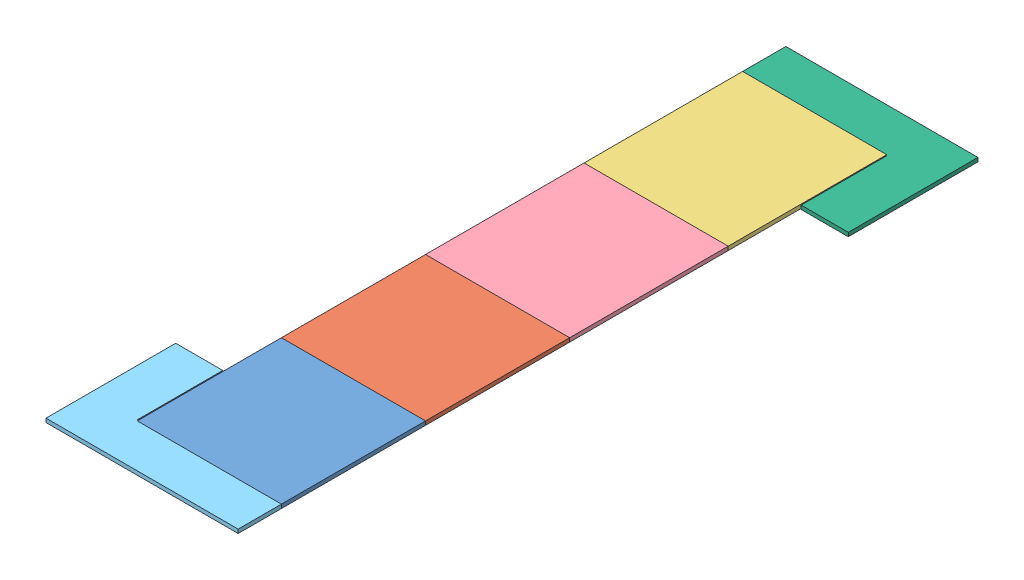
SolidWorks assembly flat, configuration Default. Lengths in mm.
Overall size (250 4 720).
6 component instances, 6 part files, 16 mates.
Components (placement in the parent):
- A-1: A [Default] at (-59.848 -4 229.8629) size (150 4 150)
- B-1: B [Default] at (-59.848 -4 229.8629) size (150 4 150)
- C-1: C [Default] at (-59.848 -4 229.8629) size (150 4 165)
- D-1: D [Default] at (-59.848 -4 229.8629) size (150 4 165)
- EA-1: EA [Default] at (-59.848 -4 229.8629) size (200 4 135)
- EC-1: EC [Default] at (-59.848 -4 229.8629) size (200 4 135)
Mates (geometry in assembly coordinates):
- Coincident3: coincident aligned: line of C-1 through (140.152 0 -280.1371) axis (-1 0 0); line of D-1 through (140.152 0 -280.1371) axis (-1 0 0)
- Coincident4: coincident aligned: line of C-1 through (-9.848 4 -445.1371) axis (1 0 0); line of EC-1 through (-9.848 4 -445.1371) axis (1 0 0)
- Coincident5: coincident aligned: plane of C-1 through (-9.848 0 229.8629) normal (-1 0 0); plane of EC-1 through (-9.848 0 229.8629) normal (-1 0 0)
- Coincident6: coincident aligned: plane of D-1 through (-9.848 0 229.8629) normal (-1 0 0); plane of EC-1 through (-9.848 0 229.8629) normal (-1 0 0)
- Coincident7: coincident aligned: line of A-1 through (140.152 4 184.8629) axis (-1 0 0); line of EA-1 through (140.152 4 184.8629) axis (-1 0 0)
- Coincident9: coincident aligned: plane of A-1 through (140.152 0 229.8629) normal (1 0 0); plane of EA-1 through (140.152 0 229.8629) normal (1 0 0)
- Coincident10: coincident aligned: plane of B-1 through (140.152 0 229.8629) normal (1 0 0); plane of EA-1 through (140.152 0 229.8629) normal (1 0 0)
- Coincident12: coincident aligned: line of A-1 through (140.152 4 34.8629) axis (-1 0 0); line of B-1 through (140.152 4 34.8629) axis (-1 0 0)
- Coincident13: coincident aligned: line of B-1 through (140.152 0 -115.1371) axis (-1 0 0); line of D-1 through (140.152 0 -115.1371) axis (-1 0 0)
- Coincident14: coincident aligned: plane of B-1 through (-9.848 0 229.8629) normal (-1 0 0); plane of D-1 through (-9.848 0 229.8629) normal (-1 0 0)
- Coincident18: coincident aligned: plane of EC-1 through (-59.848 4 229.8629) normal (0 1 0); plane of C-1 through (-59.848 4 229.8629) normal (0 1 0)
- Coincident19: coincident aligned: plane of EC-1 through (-59.848 4 229.8629) normal (0 1 0); plane of D-1 through (-59.848 4 229.8629) normal (0 1 0)
- Coincident20: coincident aligned: plane of EC-1 through (-59.848 4 229.8629) normal (0 1 0); plane of B-1 through (-59.848 4 229.8629) normal (0 1 0)
- Coincident21: coincident aligned: plane of EC-1 through (-59.848 4 229.8629) normal (0 1 0); plane of A-1 through (-59.848 4 229.8629) normal (0 1 0)
- Coincident22: coincident aligned: plane of EC-1 through (-59.848 4 229.8629) normal (0 1 0); plane of EA-1 through (-59.848 4 229.8629) normal (0 1 0)
- Coincident23: coincident anti-aligned: plane of EA-1 through (-59.848 0 229.8629) normal (0 -1 0)
